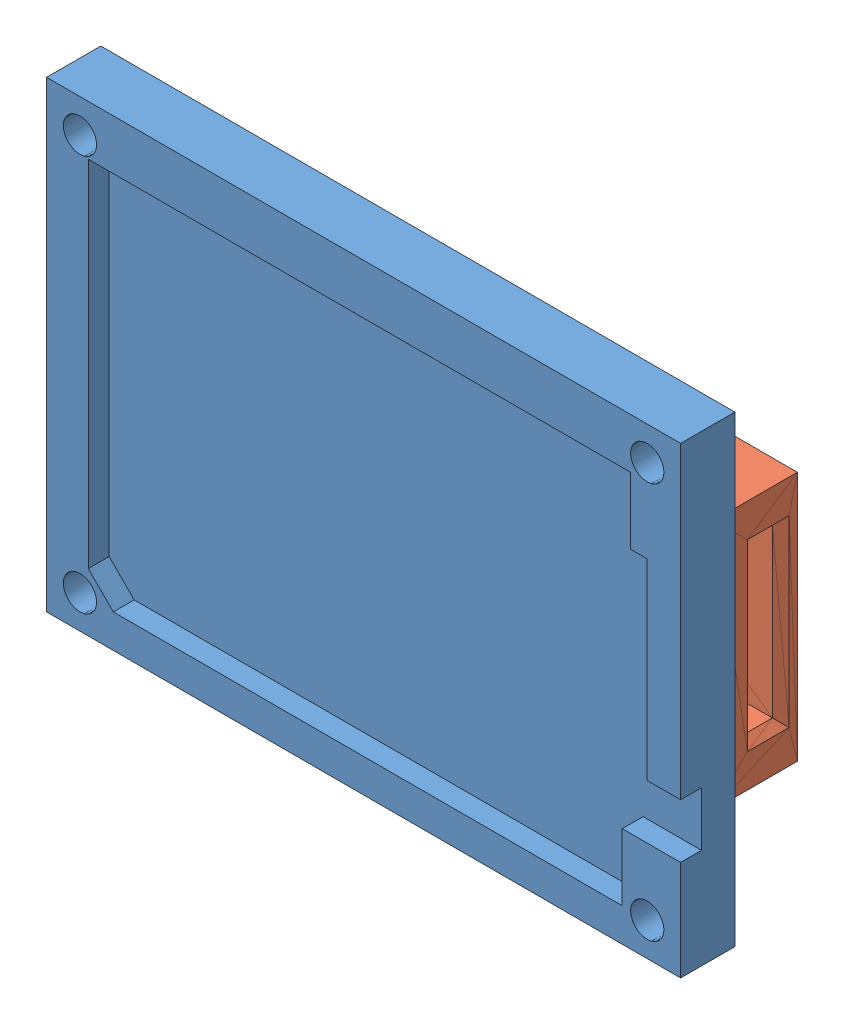
SolidWorks assembly nosilec_relay, configuration Default. Lengths in mm.
Overall size (76 55.5 16.5).
2 component instances, 2 part files, 3 mates.
Components (placement in the parent):
- relay-1: relay [Default] at (25.9772 47.4286 55.0601) size (76 55.5 6.5)
- din_nosilec-1: din_nosilec [Default] at (61.1162 57.0878 55.0601) x (-1 0 0) z (0 -1 0) size (70 10 30)
Mates (geometry in assembly coordinates):
- Coincident1: coincident: plane of relay-1 through (25.9772 47.4286 55.0601) normal (0 0 -1); plane of din_nosilec-1 through (61.1162 100.7646 55.0601) normal (0 0 1)
- Distance1: distance = 2.5 mm: plane of din_nosilec-1 through (61.1162 57.0878 55.0601) normal (1 0 0); plane of relay-1 through (63.6162 69.5878 59.0601) normal (1 0 0)
- Distance3: distance = 13 mm aligned: plane of din_nosilec-1 through (61.1162 27.0878 55.0601) normal (0 -1 0); plane of relay-1 through (-12.3838 14.0878 59.0601) normal (0 -1 0)
